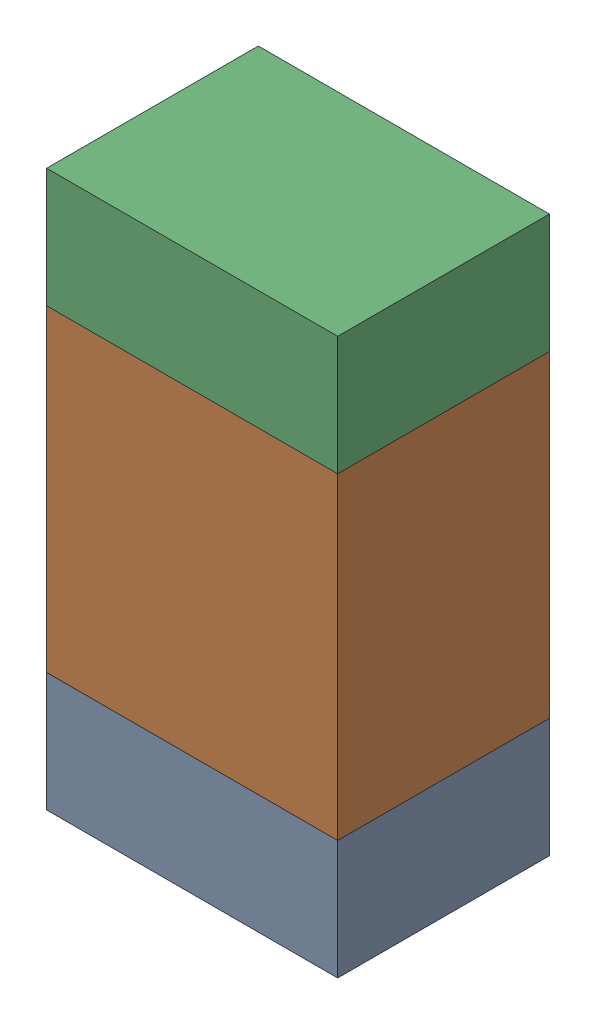
SolidWorks assembly R108_1PCB, configuration Default. Lengths in mm.
Overall size (0.55 1.05 0.4).
6 component instances, 2 part files, 0 mates.
Components (placement in the parent):
- 846483288-1: 846483288 [Default] at (115.1999 118.2876 0) size (0.55 0.22 0.4)
  - Extruded_12-1: Extruded_12 [Default] at origin size (0.55 0.22 0.4)
- 846483424-1: 846483424 [Default] at (115.1999 118.7001 0) size (0.55 0.6 0.4)
  - Extruded_13-1: Extruded_13 [Default] at origin size (0.55 0.6 0.4)
- 846483288-2: 846483288 [Default] at (115.1999 119.1126 0) size (0.55 0.22 0.4)
  - Extruded_12-1: Extruded_12 [Default] at origin size (0.55 0.22 0.4)
